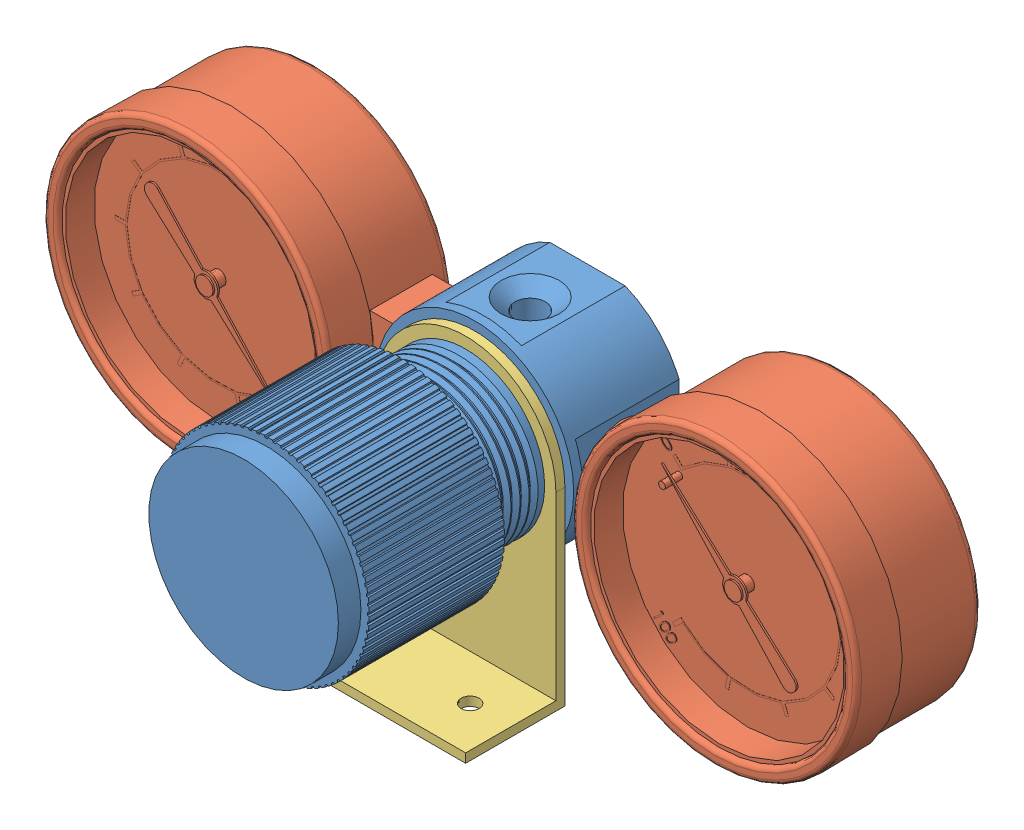
SolidWorks assembly SE_01_1_3000, configuration Default. Lengths in mm.
Overall size (180.35 73.62 76.2).
4 component instances, 3 part files, 9 mates.
Components (placement in the parent):
- SE_01_1_3001-2: SE_01_1_3001 [Default] at origin size (45.69 45.69 76.2)
- SE_01_1_3002-1: SE_01_1_3002 [Default] at (-58.5509 0 30.4289) x (0 1 0) z (0 0 1) size (63.25 91.66 28.83)
- SE_01_1_3002-2: SE_01_1_3002 [Default] at (58.5509 0 30.4289) x (0 -1 0) z (0 0 1) size (63.25 91.66 28.83)
- SE_01_1_3003-1: SE_01_1_3003 [Default] at (20 -42 25) x (0 0 1) z (-1 0 0) size (22 62 40)
Mates (geometry in assembly coordinates):
- Concentric1: concentric aligned: cylinder of SE_01_1_3001-2 through (-20.3 0 12.7) axis (-1 0 0) radius 3.3782; cylinder of SE_01_1_3002-1 through (-8.5129 0 12.7) axis (-1 0 0) radius 6.9215
- Concentric2: concentric aligned: cylinder of SE_01_1_3001-2 through (20.3 0 12.7) axis (1 0 0) radius 3.3782; cylinder of SE_01_1_3002-2 through (8.5129 0 12.7) axis (1 0 0) radius 6.9215
- Coincident1: coincident: cone of SE_01_1_3001-2 through (-20.3 0 12.7) axis (1 0 0); circle of SE_01_1_3002-1
- Coincident2: coincident: cone of SE_01_1_3001-2 through (20.3 0 12.7) axis (-1 0 0); circle of SE_01_1_3002-2
- Parallel1: parallel aligned: plane of SE_01_1_3002-2 through (58.5509 0 1.8539) normal (0 0 -1); plane of SE_01_1_3001-2 through (0 0 0) normal (0 0 -1)
- Parallel2: parallel aligned: plane of SE_01_1_3002-2 through (58.5509 0 1.8539) normal (0 0 -1); plane of SE_01_1_3002-1 through (-58.5509 0 1.8539) normal (0 0 -1)
- Concentric3: concentric: cylinder of SE_01_1_3001-2 through (0 0 76.2) axis (0 0 -1) radius 17.5; cylinder of SE_01_1_3003-1 through (0 0 28.4976) axis (0 0 1) radius 17.5
- Parallel3: parallel: plane of SE_01_1_3001-2 through (0 20.3 23) normal (0 1 0); plane of SE_01_1_3003-1 through (-20 -40 30.4986) normal (0 1 0)
- Coincident3: coincident anti-aligned: plane of SE_01_1_3001-2 through (0 0 25) normal (0 0 1); plane of SE_01_1_3003-1 through (-20 -42 25) normal (0 0 -1)
